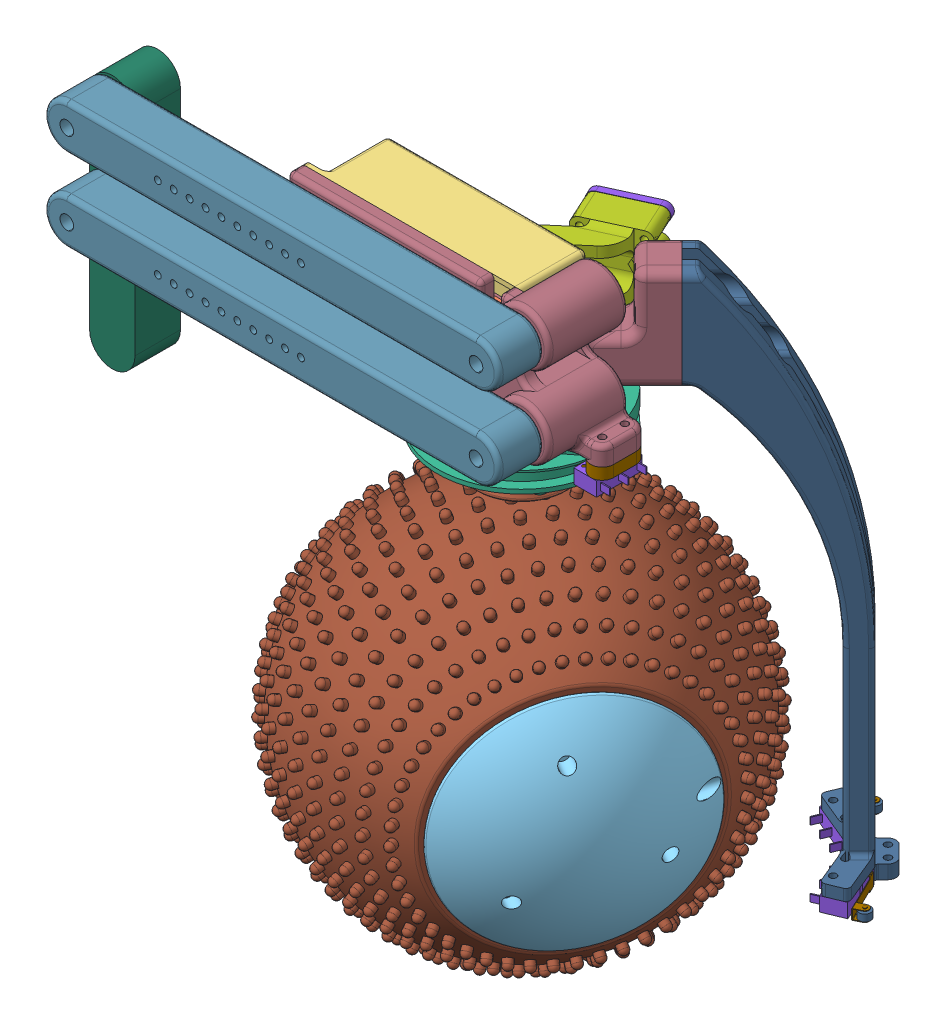
SolidWorks assembly _OmniWheel, configuration Default. Lengths in mm.
Overall size (257.35 285.35 230.93).
42 component instances, 28 part files, 105 mates.
Components (placement in the parent):
- 10mmThreadedRod-1: 10mmThreadedRod [Default] at (71.9678 -158.25 -77.1045) x (0.033468 -0.997752 -0.058051) z (0.498338 0.067008 -0.864389) size (9.53 70 9.53)
- arduino-1: arduino [Valor predeterminado] at (148.41 -2.75 -21) x (-1 0 0) z (0 0 -1) size (45.18 4.5 17.78)
- DriveMotor-1: DriveMotor [Default] at (153.4035 -158.25 -30.1552) x (-0.264151 0.848701 0.458182) z (0.423893 0.528873 -0.735261) size (25 86.5 25)
- hollowThreadedNut-1: hollowThreadedNut [Default] at (110.5631 -158.25 -54.8536) x (-0.092382 -0.982745 0.16024) z (0.490843 -0.184963 -0.851388) size (16.17 2.5 14)
- L298N Motor Driver arduino-1: L298N Motor Driver arduino [Default] at (96.25 -2.5 -9.5) x (0 1 0) z (-1 0 0) size (43.5 26 43.5)
- n20 m4x55 encoder v2-1: n20 m4x55 encoder v2 [Default] at (131.4749 -29.5 -92.3762) x (-0.417468 0 -0.908691) z (0 -1 0) size (12 10 42.21)
- slip_ring-1: slip_ring [Default] at (145 -53 -35) x (0.999063 0 0.043268) z (-0.043268 0 0.999063) size (23.5 17.5 23.5)
- switch_body-1: switch_body [Default] at (198 -38.125 -25) x (0 0 -1) z (0 1 0) size (20 14 6.25)
- switch_lever-1: switch_lever [Default] at (187.7929 -38.125 -26.5353) x (0.019708 0 -0.999806) z (0 1 0) size (20 8.75 6)
- switch_wheel-1: switch_wheel [Default] at (184.3312 -38 -34.8551) x (-0.999947 0 -0.010277) z (0 1 0) size (5 5 3)
- sphere_wheel-1: sphere_wheel [Default] at (145 -158.25 -35) x (-0.866337 0 -0.499461) z (0.492131 0.170683 -0.853624) size (125.5 168 168)
- motorMount-1: motorMount [Default] at (130.9004 -158.25 -43.1287) x (0.446555 -0.447916 -0.77457) z (-0.223716 -0.894076 0.388046) size (31.75 83.44 31.75)
- hollowThreadedNut-2: hollowThreadedNut [Default] at (123.7314 -158.25 -47.2618) x (-0.092382 -0.982745 0.16024) z (0.490843 -0.184963 -0.851388) size (16.17 2.5 14)
- hollowThreadedNut-4: hollowThreadedNut [Default] at (71.1448 -158.25 -77.579) x (0.01495 -0.999552 -0.025931) z (0.499237 0.029932 -0.865948) size (16.17 2.5 14)
- hollowThreadedNut-5: hollowThreadedNut [Default] at (87.172 -158.25 -68.339) x (0.24973 -0.866025 -0.433168) z (0.432546 0.5 -0.75027) size (16.17 2.5 14)
- suspension_mount-1: suspension_mount [Default] at (145 -30 -35) x (0 0 1) z (0 1 0) size (77.43 128.5 61.17)
- suspension_bar-1: suspension_bar [Default] at (180 18 10) size (200 20 20)
- suspension_mount_body-1: suspension_mount_body [Default] at origin size (20 111.88 20)
- bearing2-1: bearing2 [Default] at (106.448 -158.25 -57.226) x (0.296277 0.805059 -0.513906) z (0.402095 -0.593194 -0.697452) size (25 7 25)
- Wheel_cap-1: Wheel_cap [Default] at (109.4802 -158.25 -55.4779) x (0.08525 -0.985326 -0.147869) z (0.492131 0.170683 -0.853624) size (59.5 22.5 59.5)
- washer1-1: washer1 [Default] at (101.1417 -158.25 -60.2852) x (-0.362018 -0.68894 0.627937) z (0.344098 -0.724818 -0.596854) size (25 2.25 25)
- SpongeRing-1: SpongeRing [Default] at (96.052 -158.25 -63.2195) x (-0.866337 0 -0.499461) z (0.488344 -0.20981 -0.847054) size (14 51.5 51.5)
- wheel_arm-1: wheel_arm [Default] at (87.8218 -158.25 -67.9644) x (-0.866337 0 -0.499461) z (0.499461 0 -0.866337) size (108.38 170.79 80.42)
- suspension_bar-3: suspension_bar [Default] at (180 -18 10) size (200 20 20)
- suspension_mount_lid-1: suspension_mount_lid [Default] at (120 -2.5 -39) x (1 0 0) z (0 0 -1) size (96 55 30)
- bearing3-1: bearing3 [Default] at (145 -37.25 -35) x (0.997463 0 -0.071184) z (0 -1 0) size (28.5 28.5 9.5)
- 10mmThreadedRod-2: 10mmThreadedRod [short] at (145 -15 -35) x (0.211057 0 0.977474) z (-0.977474 0 0.211057) size (9.53 36 9.53)
- hollowThreadedNut-6: hollowThreadedNut [Default] at (145 -11.75 -35) x (-0.864079 0 0.503356) z (0.503356 0 0.864079) size (16.17 2.5 14)
- hollowThreadedNut-7: hollowThreadedNut [Default] at (145 -31.25 -35) x (-0.864079 0 0.503356) z (0.503356 0 0.864079) size (16.17 2.5 14)
- hollowThreadedNut-8: hollowThreadedNut [Default] at (145 -43.25 -35) x (-0.864079 0 0.503356) z (0.503356 0 0.864079) size (16.17 2.5 14)
- wheel_cap_2-1: wheel_cap_2 [Default] at (144.7834 -158.25 -35.1249) x (0.866337 0 0.499461) z (-0.08525 0.985326 0.147869) size (17.75 96.67 96.67)
- large_timing_pully-1: large_timing_pully [Default] at (145 -43 -35) x (-0.866337 0 -0.499461) z (0.499461 0 -0.866337) size (73.67 25.42 73.67)
- micro_gear_motor_casing_A-1: micro_gear_motor_casing_A [Default] at (131.4529 -22 -92.3705) x (-0.417468 0 -0.908691) z (0.908691 0 -0.417468) size (33.5 37.27 49.25)
- micro_gear_motor_casing_B-1: micro_gear_motor_casing_B [Default] at (128.2175 -22 -99.4128) x (-0.908691 0 0.417468) z (-0.417468 0 -0.908691) size (28.5 37.25 3)
- switch_spacer-1: switch_spacer [Default] at (195.5 -32.5 -25) x (0 0 -1) z (1 0 0) size (20 5 10)
- sensorArray_frame-1: sensorArray_frame [Default] at (180.3553 -7.5 -70.3553) x (-0.707107 0 0.707107) z (-0.707107 0 -0.707107) size (67.99 233.5 54.5)
- switch_body-2: switch_body [Default] at (202.791 -215.625 -113.7167) x (-0.92388 0 -0.382683) z (0 -1 0) size (20 14 6.25)
- switch_lever-2: switch_lever [Default] at (206.7215 -215.625 -125.3908) x (-0.810364 0 -0.585927) z (0 -1 0) size (20 8.75 6)
- switch_wheel-2: switch_wheel [Default] at (202.16 -215.625 -133.1622) x (0.999993 0 -0.003676) z (0 -1 0) size (5 5 3)
- switch_body-3: switch_body [Default] at (223.7167 -215.625 -92.791) x (0.382683 0 0.92388) z (0 1 0) size (20 14 6.25)
- switch_lever-3: switch_lever [Default] at (234.3073 -215.625 -95.6971) x (0.439028 0 0.898473) z (0 1 0) size (20 8.75 6)
- switch_wheel-3: switch_wheel [Default] at (241.1863 -215.625 -89.8762) x (-0.999993 0 -0.003746) z (0 1 0) size (5 5 3)
Mates (geometry in assembly coordinates):
- Concentric1: concentric aligned: cylinder of DriveMotor-1 through (197.1535 -158.25 -4.9325) axis (-0.866337 0 -0.499461) radius 12.5; cylinder of sphere_wheel-1 through (208.2426 -158.25 1.4606) axis (-0.866337 0 -0.499461) radius 25
- Concentric2: concentric aligned: cylinder of DriveMotor-1 through (173.7624 -158.25 -18.4179) axis (-0.866337 0 -0.499461) radius 12.2; cylinder of motorMount-1 through (183.9323 -158.25 -12.5547) axis (-0.866337 0 -0.499461) radius 12.7
- Concentric4: concentric aligned: cylinder of 10mmThreadedRod-1 through (15.6559 -158.25 -109.5695) axis (0.866337 0 0.499461) radius 4.7625; cylinder of motorMount-1 through (111.646 -158.25 -54.2292) axis (0.866337 0 0.499461) radius 4.7625
- Concentric5: concentric aligned: cylinder of 10mmThreadedRod-1 through (15.6559 -158.25 -109.5695) axis (0.866337 0 0.499461) radius 4.7625; cylinder of hollowThreadedNut-1 through (109.4802 -158.25 -55.4779) axis (0.866337 0 0.499461) radius 5
- Concentric6: concentric aligned: cylinder of 10mmThreadedRod-1 through (15.6559 -158.25 -109.5695) axis (0.866337 0 0.499461) radius 4.7625; cylinder of hollowThreadedNut-2 through (122.6485 -158.25 -47.8861) axis (0.866337 0 0.499461) radius 5
- Coincident1: coincident anti-aligned: plane of motorMount-1 through (122.6485 -158.25 -47.8861) normal (0.866337 0 0.499461); plane of hollowThreadedNut-2 through (122.6485 -158.25 -47.8861) normal (-0.866337 0 -0.499461)
- Coincident2: coincident anti-aligned: plane of hollowThreadedNut-1 through (111.646 -158.25 -54.2292) normal (0.866337 0 0.499461); plane of motorMount-1 through (111.646 -158.25 -54.2292) normal (-0.866337 0 -0.499461)
- Concentric9: concentric aligned: cylinder of 10mmThreadedRod-1 through (15.6559 -158.25 -109.5695) axis (0.866337 0 0.499461) radius 4.7625; cylinder of hollowThreadedNut-4 through (70.0619 -158.25 -78.2033) axis (0.866337 0 0.499461) radius 5
- Concentric10: concentric aligned: cylinder of 10mmThreadedRod-1 through (15.6559 -158.25 -109.5695) axis (0.866337 0 0.499461) radius 4.7625; cylinder of hollowThreadedNut-5 through (86.0891 -158.25 -68.9633) axis (0.866337 0 0.499461) radius 5
- Concentric11: concentric aligned: cylinder of switch_body-1 through (189.5 -35 -18) axis (0 -1 0) radius 0.75; cylinder of switch_lever-1 through (189.5 -36.125 -18) axis (0 -1 0) radius 1.5
- Width1: width anti-aligned: plane of switch_body-1 through (198 -41.25 -25) normal (0 -1 0); plane of switch_body-1 through (198 -35 -25) normal (0 1 0); plane of switch_lever-1 through (187.7799 -40.875 -19.5342) normal (0 1 0); plane of switch_lever-1 through (187.7799 -35.375 -19.5342) normal (0 -1 0)
- Concentric12: concentric aligned: cylinder of switch_lever-1 through (184.3312 -35.625 -34.8551) axis (0 -1 0) radius 0.75; cylinder of switch_wheel-1 through (184.3312 -36.5 -34.8551) axis (0 -1 0) radius 2.5
- Concentric18: concentric anti-aligned: cylinder of 10mmThreadedRod-1 through (15.6559 -158.25 -109.5695) axis (0.866337 0 0.499461) radius 4.7625; cylinder of bearing2-1 through (109.4802 -158.25 -55.4779) axis (-0.866337 0 -0.499461) radius 5
- Coincident24: coincident anti-aligned: plane of hollowThreadedNut-1 through (109.4802 -158.25 -55.4779) normal (-0.866337 0 -0.499461); plane of bearing2-1 through (109.4802 -158.25 -55.4779) normal (0.866337 0 0.499461)
- Concentric19: concentric anti-aligned: cylinder of bearing2-1 through (109.4802 -158.25 -55.4779) axis (-0.866337 0 -0.499461) radius 11; cylinder of Wheel_cap-1 through (89.9876 -158.25 -66.7157) axis (0.866337 0 0.499461) radius 11.125
- Coincident25: coincident anti-aligned: plane of bearing2-1 through (108.1807 -158.25 -56.2271) normal (-0.866337 0 -0.499461); plane of Wheel_cap-1 through (108.1807 -158.25 -56.2271) normal (0.866337 0 0.499461)
- Parallel1: parallel anti-aligned: plane of sphere_wheel-1 through (145 -158.25 -35) normal (-0.08525 0.985326 0.147869); plane of Wheel_cap-1 through (109.4802 -158.25 -55.4779) normal (0.08525 -0.985326 -0.147869)
- Concentric20: concentric aligned: cylinder of 10mmThreadedRod-1 through (15.6559 -158.25 -109.5695) axis (0.866337 0 0.499461) radius 4.7625; cylinder of washer1-1 through (100.1671 -158.25 -60.8471) axis (0.866337 0 0.499461) radius 5.75
- Coincident26: coincident anti-aligned: plane of Wheel_cap-1 through (102.1163 -158.25 -59.7233) normal (-0.866337 0 -0.499461); plane of washer1-1 through (102.1163 -158.25 -59.7233) normal (0.866337 0 0.499461)
- Tangent1: tangent anti-aligned: cylinder of Wheel_cap-1 through (120.2231 -153.172 -83.1216) axis (-0.492131 -0.170683 0.853624) radius 4; plane of SpongeRing-1 through (103.5834 -144.5616 -62.268) normal (0.866337 0 0.499461)
- Concentric21: concentric aligned: cylinder of Wheel_cap-1 through (107.3144 -158.25 -56.7265) axis (-0.866337 0 -0.499461) radius 26; cylinder of SpongeRing-1 through (96.052 -158.25 -63.2195) axis (-0.866337 0 -0.499461) radius 25.75
- Concentric22: concentric aligned: cylinder of 10mmThreadedRod-1 through (15.6559 -158.25 -109.5695) axis (0.866337 0 0.499461) radius 4.7625; cylinder of wheel_arm-1 through (75.6931 -158.25 -74.9568) axis (0.866337 0 0.499461) radius 4.7625
- Concentric24: concentric: sphere of sphere_wheel-1; sphere of wheel_arm-1
- Parallel2: parallel anti-aligned: plane of hollowThreadedNut-5 through (84.0706 -151.25 -65.4621) normal (0 1 0); plane of wheel_arm-1 through (88.1437 -151.125 -72.5271) normal (0 -1 0)
- Coincident27: coincident anti-aligned: plane of hollowThreadedNut-5 through (86.0891 -158.25 -68.9633) normal (-0.866337 0 -0.499461); plane of wheel_arm-1 through (86.0891 -158.25 -68.9633) normal (0.866337 0 0.499461)
- Concentric26: concentric anti-aligned: cylinder of slip_ring-1 through (145 -61.75 -35) axis (0 -1 0) radius 6.25; cylinder of wheel_arm-1 through (145 -66.25 -35) axis (0 1 0) radius 20
- Distance2: distance = 12 mm anti-aligned: plane of DriveMotor-1 through (133.0446 -158.25 -41.8926) normal (-0.866337 0 -0.499461); plane of motorMount-1 through (122.6485 -158.25 -47.8861) normal (0.866337 0 0.499461)
- Coincident28: coincident anti-aligned: plane of hollowThreadedNut-4 through (72.2277 -158.25 -76.9547) normal (0.866337 0 0.499461); plane of wheel_arm-1 through (72.2277 -158.25 -76.9547) normal (-0.866337 0 -0.499461)
- Distance3: distance = 4 mm aligned: plane of hollowThreadedNut-2 through (124.8144 -158.25 -46.6374) normal (0.866337 0 0.499461); plane of 10mmThreadedRod-1 through (128.2797 -158.25 -44.6396) normal (0.866337 0 0.499461)
- Coincident30: coincident anti-aligned: plane of slip_ring-1 through (133.261 -48.25 -35.5084) normal (0 -1 0); plane of wheel_arm-1 through (145 -48.25 -35) normal (0 1 0)
- Concentric28: concentric anti-aligned: cylinder of suspension_mount-1 through (145 30 -35) axis (0 -1 0) radius 20; cylinder of wheel_arm-1 through (145 -66.25 -35) axis (0 1 0) radius 20
- Parallel4: parallel aligned: cylinder of n20 m4x55 encoder v2-1 through (131.4529 -32.9733 -92.3705) axis (0 -1 0) radius 1.954; cylinder of suspension_mount-1 through (145 30 -35) axis (0 -1 0) radius 20
- Parallel5: parallel aligned: plane of suspension_mount-1 through (145 -30 -35) normal (0 0 1)
- Concentric33: concentric aligned: cylinder of suspension_mount-1 through (180 18 -15) axis (0 0 -1) radius 3; cylinder of suspension_bar-1 through (180 18 20) axis (0 0 -1) radius 3
- Coincident32: coincident aligned: plane of suspension_bar-1 through (0 18 20) normal (0 0 1); plane of suspension_bar-3 through (0 -18 20) normal (0 0 1)
- Concentric42: concentric aligned: cylinder of suspension_mount-1 through (180 -18 -15) axis (0 0 -1) radius 3; cylinder of suspension_bar-3 through (180 -18 20) axis (0 0 -1) radius 3
- Coincident33: coordinate: point of suspension_mount_body-1
- Concentric45: concentric anti-aligned: cylinder of suspension_bar-1 through (0 18 20) axis (0 0 -1) radius 3; cylinder of suspension_mount_body-1 through (0 18 -20) axis (0 0 1) radius 3
- Concentric46: concentric anti-aligned: cylinder of suspension_mount_body-1 through (0 -18 -20) axis (0 0 1) radius 3; cylinder of suspension_bar-3 through (0 -18 20) axis (0 0 -1) radius 3
- Coincident34: coincident anti-aligned: plane of suspension_mount-1 through (180 18 0) normal (0 0 1); plane of suspension_bar-1 through (0 18 0) normal (0 0 -1)
- Coincident35: coincident anti-aligned: plane of suspension_mount_body-1 through (0 18 0) normal (0 0 1); plane of suspension_bar-3 through (0 -18 0) normal (0 0 -1)
- Parallel8: parallel aligned: plane of L298N Motor Driver arduino-1 through (96.25 -2.5 -11) normal (0 0 -1); plane of suspension_mount-1 through (180 18 -7) normal (0 0 -1)
- Parallel9: parallel aligned: plane of L298N Motor Driver arduino-1 through (74.5 -24.25 -11) normal (0 -1 0); plane of suspension_mount-1 through (145 -30 -35) normal (0 -1 0)
- Parallel11: parallel aligned: plane of arduino-1 through (148.41 -1.75 -21) normal (0 1 0); plane of suspension_mount-1 through (168 -10 -55) normal (0 1 0)
- Concentric47: concentric anti-aligned: cylinder of L298N Motor Driver arduino-1 through (115 16.25 -11) axis (0 0 1) radius 1.5; cylinder of suspension_mount-1 through (115 16.25 0) axis (0 0 -1) radius 1.5
- Concentric48: concentric anti-aligned: cylinder of L298N Motor Driver arduino-1 through (77.5 -21.25 -11) axis (0 0 1) radius 1.5; cylinder of suspension_mount-1 through (77.5 -21.25 0) axis (0 0 -1) radius 1.5
- Coincident36: coincident anti-aligned: plane of L298N Motor Driver arduino-1 through (96.25 -2.5 -9.5) normal (0 0 1); plane of suspension_mount-1 through (77.5 -21.25 -9.5) normal (0 0 -1)
- Width3: width anti-aligned: plane of suspension_mount-1 through (170 -3.5 -30) normal (0 0 1); plane of arduino-1 through (170 -3.5 -12) normal (0 0 -1); plane of suspension_mount-1 through (170 -1.75 -29.89) normal (0 0 -1); plane of arduino-1 through (170 -1.75 -12.11) normal (0 0 1)
- Coincident37: coincident anti-aligned: plane of arduino-1 through (170 -1.75 -29.89) normal (1 0 0); plane of suspension_mount-1 through (170 -30 -35) normal (-1 0 0)
- Width4: width aligned: plane of suspension_mount-1 through (192 -2.25 -25.25) normal (0 1 0); plane of arduino-1 through (192 2.25 -25.25) normal (0 -1 0); plane of suspension_mount-1 through (148.41 1.75 -21) normal (0 1 0); plane of arduino-1 through (148.41 -1.75 -21) normal (0 -1 0)
- Coincident38: coincident aligned: plane of suspension_mount-1 through (170.2532 25 -7) normal (0 1 0); plane of suspension_mount_lid-1 through (72 25 -41) normal (0 1 0)
- Coincident39: coincident aligned: plane of suspension_mount-1 through (72 25 -7) normal (-1 0 0); plane of suspension_mount_lid-1 through (72 25 -41) normal (-1 0 0)
- Coincident40: coincident anti-aligned: plane of suspension_mount-1 through (161 15 -11) normal (0 0 -1); plane of suspension_mount_lid-1 through (120 -2.5 -11) normal (0 0 1)
- Concentric49: concentric aligned: cylinder of wheel_arm-1 through (145 -66.25 -35) axis (0 1 0) radius 20; cylinder of bearing3-1 through (145 -42 -35) axis (0 1 0) radius 14.25
- Concentric50: concentric anti-aligned: cylinder of suspension_mount-1 through (145 -30 -35) axis (0 1 0) radius 4.7625; cylinder of 10mmThreadedRod-2 through (145 50 -35) axis (0 -1 0) radius 4.7625
- Concentric51: concentric anti-aligned: cylinder of 10mmThreadedRod-2 through (145 50 -35) axis (0 -1 0) radius 4.7625; cylinder of hollowThreadedNut-6 through (145 -13 -35) axis (0 1 0) radius 5
- Coincident42: coincident anti-aligned: plane of suspension_mount-1 through (145 -13 -35) normal (0 1 0); plane of hollowThreadedNut-6 through (145 -13 -35) normal (0 -1 0)
- Coincident43: coincident aligned: plane of suspension_mount-1 through (168 -10 -55) normal (0 1 0); plane of 10mmThreadedRod-2 through (159.2034 -10 -42.9391) normal (0 1 0)
- Concentric52: concentric anti-aligned: cylinder of 10mmThreadedRod-2 through (145 50 -35) axis (0 -1 0) radius 4.7625; cylinder of hollowThreadedNut-7 through (145 -32.5 -35) axis (0 1 0) radius 5
- Coincident44: coincident anti-aligned: plane of suspension_mount-1 through (145 -30 -35) normal (0 -1 0); plane of hollowThreadedNut-7 through (145 -30 -35) normal (0 1 0)
- Coincident45: coincident anti-aligned: plane of bearing3-1 through (145 -32.5 -35) normal (0 1 0); plane of hollowThreadedNut-7 through (145 -32.5 -35) normal (0 -1 0)
- Concentric53: concentric anti-aligned: cylinder of 10mmThreadedRod-2 through (145 50 -35) axis (0 -1 0) radius 4.7625; cylinder of hollowThreadedNut-8 through (145 -44.5 -35) axis (0 1 0) radius 5
- Coincident46: coincident anti-aligned: plane of bearing3-1 through (145 -42 -35) normal (0 -1 0); plane of hollowThreadedNut-8 through (145 -42 -35) normal (0 1 0)
- Coincident47: coincident anti-aligned: plane of wheel_arm-1 through (127.6535 -42 -39.8063) normal (0 1 0); plane of bearing3-1 through (145 -42 -35) normal (0 -1 0)
- Coincident48: coincident anti-aligned: plane of sphere_wheel-1 through (198.7129 -158.25 -4.0334) normal (0.866337 0 0.499461); plane of wheel_cap_2-1 through (223.4419 -149.6734 -46.927) normal (-0.866337 0 -0.499461)
- Concentric54: concentric aligned: cylinder of sphere_wheel-1 through (208.2426 -158.25 1.4606) axis (-0.866337 0 -0.499461) radius 25; cylinder of wheel_cap_2-1 through (211.7079 -158.25 3.4585) axis (-0.866337 0 -0.499461) radius 2
- Parallel12: parallel aligned: plane of sphere_wheel-1 through (145 -158.25 -35) normal (-0.08525 0.985326 0.147869); plane of wheel_cap_2-1 through (144.7834 -158.25 -35.1249) normal (-0.08525 0.985326 0.147869)
- Concentric55: concentric anti-aligned: cylinder of wheel_arm-1 through (145 -66.25 -35) axis (0 1 0) radius 20; cylinder of large_timing_pully-1 through (145 -43 -35) axis (0 -1 0) radius 20.25
- Parallel13: parallel aligned: plane of wheel_arm-1 through (87.8218 -158.25 -67.9644) normal (0.499461 0 -0.866337); plane of large_timing_pully-1 through (145 -43 -35) normal (0.499461 0 -0.866337)
- Parallel14: parallel aligned: plane of n20 m4x55 encoder v2-1 through (129.4363 -29.5 -84.8367) normal (-0.908691 0 0.417468); plane of micro_gear_motor_casing_A-1 through (133.6143 -5.5 -100.2415) normal (-0.908691 0 0.417468)
- Concentric58: concentric anti-aligned: cylinder of n20 m4x55 encoder v2-1 through (131.4529 -32.9733 -92.3705) axis (0 -1 0) radius 1.954; cylinder of micro_gear_motor_casing_A-1 through (131.4529 -42.7361 -92.3705) axis (0 1 0) radius 6.4971
- Coincident49: coincident anti-aligned: plane of n20 m4x55 encoder v2-1 through (131.4749 -38.5 -92.3762) normal (0 -1 0); plane of micro_gear_motor_casing_A-1 through (131.4529 -38.5 -92.3705) normal (0 1 0)
- Distance4: distance = 3.5 mm aligned: plane of wheel_arm-1 through (127.6535 -32 -39.8063) normal (0 1 0); plane of large_timing_pully-1 through (127.4567 -35.5 -45.1141) normal (0 1 0)
- Concentric59: concentric anti-aligned: cylinder of micro_gear_motor_casing_A-1 through (125.1286 -37.125 -80.386) axis (-0.417468 0 -0.908691) radius 1.4; cylinder of micro_gear_motor_casing_B-1 through (117.8229 -37.125 -96.2881) axis (0.417468 0 0.908691) radius 1.5
- Concentric60: concentric anti-aligned: cylinder of micro_gear_motor_casing_A-1 through (144.6654 -6.875 -89.3616) axis (-0.417468 0 -0.908691) radius 1.4; cylinder of micro_gear_motor_casing_B-1 through (137.3597 -6.875 -105.2637) axis (0.417468 0 0.908691) radius 1.5
- Coincident50: coincident anti-aligned: plane of micro_gear_motor_casing_A-1 through (135.4317 -5.5 -101.0764) normal (-0.417468 0 -0.908691); plane of micro_gear_motor_casing_B-1 through (138.6121 -13.875 -102.5376) normal (0.417468 0 0.908691)
- Coincident51: coincident anti-aligned: plane of sphere_wheel-1 through (106.9227 -128.6902 -51.0418) normal (-0.866337 0 -0.499461); plane of Wheel_cap-1 through (109.4802 -158.25 -55.4779) normal (0.866337 0 0.499461)
- Concentric61: concentric aligned: cylinder of suspension_mount-1 through (113.4808 -25 -59.628) axis (0 1 0) radius 2; cylinder of micro_gear_motor_casing_A-1 through (113.4808 -30 -59.628) axis (0 1 0) radius 2
- Width5: width aligned: plane of suspension_mount-1 through (168 -10 -55) normal (0 1 0); plane of micro_gear_motor_casing_A-1 through (145 -25 -35) normal (0 -1 0); plane of suspension_mount-1 through (131.4529 -25.25 -92.3705) normal (0 1 0); plane of micro_gear_motor_casing_A-1 through (131.4529 -9.75 -92.3705) normal (0 -1 0)
- Concentric62: concentric aligned: cylinder of switch_body-1 through (195.5 -35 -30) axis (0 -1 0) radius 1.5; cylinder of suspension_mount-1 through (195.5 -22 -30) axis (0 -1 0) radius 1.5
- Concentric63: concentric aligned: cylinder of switch_body-1 through (195.5 -35 -20) axis (0 -1 0) radius 1.5; cylinder of suspension_mount-1 through (195.5 -22 -20) axis (0 -1 0) radius 1.5
- Concentric64: concentric aligned: cylinder of suspension_mount-1 through (195.5 -22 -20) axis (0 -1 0) radius 1.5; cylinder of switch_spacer-1 through (195.5 -30 -20) axis (0 -1 0) radius 1.6
- Concentric65: concentric aligned: cylinder of suspension_mount-1 through (195.5 -22 -30) axis (0 -1 0) radius 1.5; cylinder of switch_spacer-1 through (195.5 -30 -30) axis (0 -1 0) radius 1.6
- Coincident52: coincident anti-aligned: plane of suspension_mount-1 through (145 -30 -35) normal (0 -1 0); plane of switch_spacer-1 through (195.5 -30 -30) normal (0 1 0)
- Coincident53: coincident anti-aligned: plane of switch_body-1 through (198 -35 -25) normal (0 1 0); plane of switch_spacer-1 through (195.5 -35 -30) normal (0 -1 0)
- PathMate2: path: circle of switch_wheel-1; curve of large_timing_pully-1
- PathMate3: path: unknown of switch_wheel-1; edge_curve of large_timing_pully-1
- Coincident54: coincident anti-aligned: plane of suspension_mount-1 through (187.4264 -30 -63.2843) normal (0.707107 0 -0.707107); plane of sensorArray_frame-1 through (173.2843 -30 -77.4264) normal (-0.707107 0 0.707107)
- Width6: width aligned: plane of sensorArray_frame-1 through (116.7157 -128.3616 -20.8579) normal (-0.707107 0 -0.707107); plane of sensorArray_frame-1 through (130.8579 -128.3616 -6.7157) normal (0.707107 0 0.707107); plane of suspension_mount-1 through (150.1764 -30 -54.3185) normal (-0.707107 0 -0.707107); plane of suspension_mount-1 through (164.3185 -30 -40.1764) normal (0.707107 0 0.707107)
- Coincident56: coincident aligned: plane of suspension_mount-1 through (176.8198 15 -52.6777) normal (0 1 0); plane of sensorArray_frame-1 through (173.2843 15 -77.4264) normal (0 1 0)
- Concentric66: concentric aligned: cylinder of switch_body-2 through (212.511 -218.75 -118.8909) axis (0 1 0) radius 0.75; cylinder of switch_lever-2 through (212.511 -218.375 -118.8909) axis (0 1 0) radius 1.5
- Concentric67: concentric aligned: cylinder of switch_lever-2 through (202.16 -218.125 -133.1622) axis (0 1 0) radius 0.75; cylinder of switch_wheel-2 through (202.16 -217.125 -133.1622) axis (0 1 0) radius 2.5
- Width7: width aligned: plane of switch_lever-2 through (201.3809 -217.875 -129.098) normal (0 -1 0); plane of switch_lever-2 through (201.3809 -213.375 -129.098) normal (0 1 0); plane of switch_wheel-2 through (202.16 -217.125 -133.1622) normal (0 -1 0); plane of switch_wheel-2 through (202.16 -214.125 -133.1622) normal (0 1 0)
- Width8: width anti-aligned: plane of switch_body-2 through (202.791 -212.5 -113.7167) normal (0 1 0); plane of switch_body-2 through (202.791 -218.75 -113.7167) normal (0 -1 0); plane of switch_lever-2 through (212.3208 -212.875 -121.188) normal (0 -1 0); plane of switch_lever-2 through (212.3208 -218.375 -121.188) normal (0 1 0)
- Coincident57: coincident anti-aligned: plane of sensorArray_frame-1 through (208.6396 -212.5 -112.7817) normal (0 -1 0); plane of switch_body-2 through (202.791 -212.5 -113.7167) normal (0 1 0)
- Parallel15: parallel aligned: plane of sensorArray_frame-1 through (193.5522 -207.5 -117.5436) normal (-0.382683 0 0.92388); plane of switch_body-2 through (193.5522 -218.75 -117.5436) normal (-0.382683 0 0.92388)
- Coincident58: coincident aligned: plane of sensorArray_frame-1 through (197.3791 -207.5 -126.7824) normal (-0.92388 0 -0.382683); plane of switch_body-2 through (197.1877 -218.75 -126.3204) normal (-0.92388 0 -0.382683)
- Coincident59: coincident aligned: plane of sensorArray_frame-1 through (216.476 -207.5 -118.8721) normal (0.382683 0 -0.92388); plane of switch_body-2 through (215.8566 -218.75 -119.1287) normal (0.382683 0 -0.92388)
- Concentric68: concentric aligned: cylinder of switch_lever-3 through (241.1863 -213.125 -89.8762) axis (0 -1 0) radius 0.75; cylinder of switch_wheel-3 through (241.1863 -214.125 -89.8762) axis (0 -1 0) radius 2.5
- Width9: width aligned: plane of switch_lever-3 through (237.0487 -213.375 -89.8022) normal (0 1 0); plane of switch_lever-3 through (237.0487 -217.875 -89.8022) normal (0 -1 0); plane of switch_wheel-3 through (241.1863 -214.125 -89.8762) normal (0 1 0); plane of switch_wheel-3 through (241.1863 -217.125 -89.8762) normal (0 -1 0)
- Concentric69: concentric aligned: cylinder of switch_body-3 through (228.8909 -212.5 -102.511) axis (0 -1 0) radius 0.75; cylinder of switch_lever-3 through (228.8909 -213.625 -102.511) axis (0 -1 0) radius 1.5
- Width10: width aligned: plane of switch_body-3 through (223.7167 -218.75 -92.791) normal (0 -1 0); plane of switch_body-3 through (223.7167 -212.5 -92.791) normal (0 1 0); plane of switch_lever-3 through (228.2018 -218.625 -100.5047) normal (0 -1 0); plane of switch_lever-3 through (228.2018 -212.625 -100.5047) normal (0 1 0)
- Coincident60: coincident anti-aligned: plane of sensorArray_frame-1 through (208.6396 -212.5 -112.7817) normal (0 -1 0); plane of switch_body-3 through (223.7167 -212.5 -92.791) normal (0 1 0)
- Concentric70: concentric aligned: cylinder of sensorArray_frame-1 through (224.113 -207.5 -98.3671) axis (0 -1 0) radius 1.5; cylinder of switch_body-3 through (224.113 -212.5 -98.3671) axis (0 -1 0) radius 1.5
- Concentric71: concentric aligned: cylinder of sensorArray_frame-1 through (227.9399 -207.5 -89.1283) axis (0 -1 0) radius 1.5; cylinder of switch_body-3 through (227.9399 -212.5 -89.1283) axis (0 -1 0) radius 1.5
